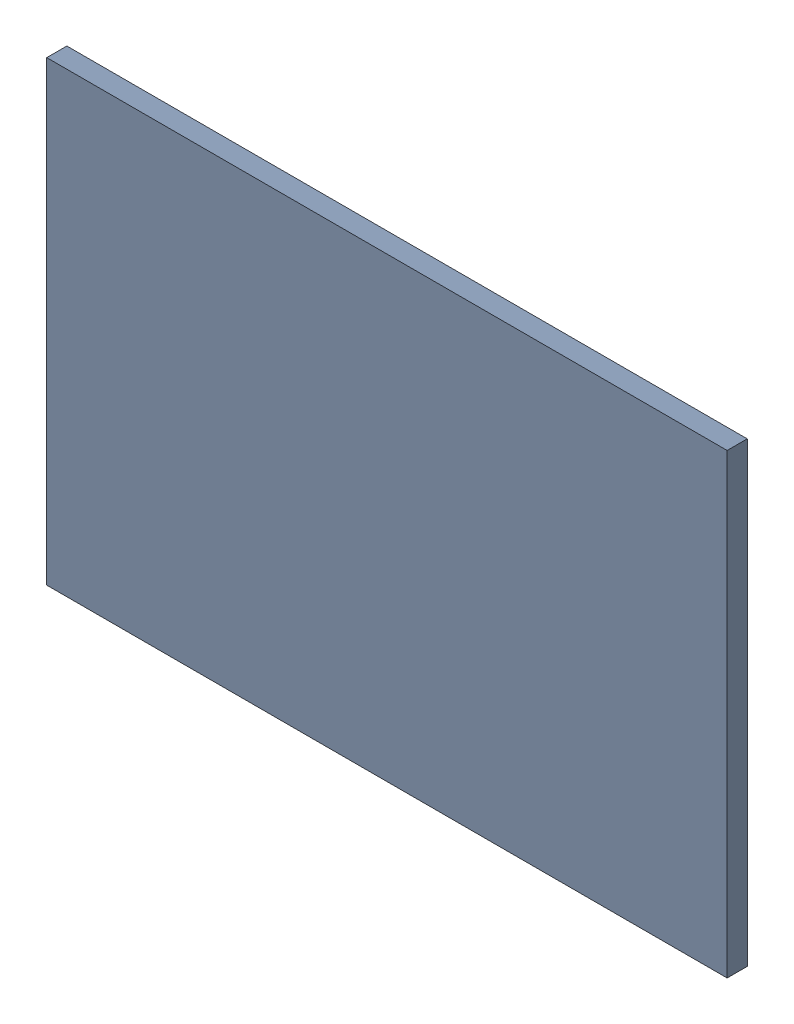
SolidWorks assembly terain complet, configuration Défaut. Lengths in mm.
Overall size (3044 2044 135).
55 component instances, 2 part files, 183 mates.
Components (placement in the parent):
- Pièce1-1: Pièce1 [Défaut] at (-264.4399 -325.1488 85) size (3044 2044 90)
- blocs-1: blocs [Défaut] at (410.3862 -144.8276 85) x (-1 0 0) z (0 0 -1) size (50 150 30)
- blocs-2: blocs [Défaut] at (357.991 -144.8276 55) size (50 150 30)
- blocs-3: blocs [Défaut] at (257.991 -144.8276 55) size (50 150 30)
- blocs-4: blocs [Défaut] at (310.3862 -144.8276 85) x (-1 0 0) z (0 0 -1) size (50 150 30)
- blocs-5: blocs [Défaut] at (-391.0933 -149.325 85) x (-1 0 0) z (0 0 -1) size (50 150 30)
- blocs-6: blocs [Défaut] at (-443.4885 -149.325 55) size (50 150 30)
- blocs-7: blocs [Défaut] at (-343.4885 -149.325 55) size (50 150 30)
- blocs-8: blocs [Défaut] at (-291.0933 -149.325 85) x (-1 0 0) z (0 0 -1) size (50 150 30)
- blocs-13: blocs [Défaut] at (-440.056 -818.8868 85) x (-1 0 0) z (0 0 -1) size (50 150 30)
- blocs-14: blocs [Défaut] at (-492.4513 -818.8868 55) size (50 150 30)
- blocs-15: blocs [Défaut] at (-392.4513 -818.8868 55) size (50 150 30)
- blocs-16: blocs [Défaut] at (-340.056 -818.8868 85) x (-1 0 0) z (0 0 -1) size (50 150 30)
- blocs-17: blocs [Défaut] at (408.6979 -820.0793 55) size (50 150 30)
- blocs-18: blocs [Défaut] at (461.0931 -820.0793 85) x (-1 0 0) z (0 0 -1) size (50 150 30)
- blocs-19: blocs [Défaut] at (361.0931 -820.0793 85) x (-1 0 0) z (0 0 -1) size (50 150 30)
- blocs-20: blocs [Défaut] at (308.6979 -820.0793 55) size (50 150 30)
- blocs-21: blocs [Défaut] at (-1350.1941 240.0301 85) x (0 1 0) z (0 0 -1) size (50 150 30)
- blocs-22: blocs [Défaut] at (-1350.1941 292.4253 55) x (0 -1 0) z (0 0 1) size (50 150 30)
- blocs-23: blocs [Défaut] at (-1350.1941 192.4253 55) x (0 -1 0) z (0 0 1) size (50 150 30)
- blocs-24: blocs [Défaut] at (-1350.1941 140.0301 85) x (0 1 0) z (0 0 -1) size (50 150 30)
- blocs-25: blocs [Défaut] at (-1428.6972 -611.7419 85) x (0 -1 0) z (0 0 -1) size (50 150 30)
- blocs-26: blocs [Défaut] at (-1428.6972 -664.1371 55) x (0 1 0) z (0 0 1) size (50 150 30)
- blocs-27: blocs [Défaut] at (-1428.6972 -564.1371 55) x (0 1 0) z (0 0 1) size (50 150 30)
- blocs-28: blocs [Défaut] at (-1428.6972 -511.7419 85) x (0 -1 0) z (0 0 -1) size (50 150 30)
- blocs-29: blocs [Défaut] at (1322.3512 -560.3529 55) x (0 1 0) z (0 0 1) size (50 150 30)
- blocs-30: blocs [Défaut] at (1322.3512 -660.3529 55) x (0 1 0) z (0 0 1) size (50 150 30)
- blocs-31: blocs [Défaut] at (1322.3512 -607.9577 85) x (0 -1 0) z (0 0 -1) size (50 150 30)
- blocs-32: blocs [Défaut] at (1396.9289 190.9777 55) x (0 -1 0) z (0 0 1) size (50 150 30)
- blocs-33: blocs [Défaut] at (1322.3512 -507.9577 85) x (0 -1 0) z (0 0 -1) size (50 150 30)
- blocs-34: blocs [Défaut] at (1396.9289 138.5825 85) x (0 1 0) z (0 0 -1) size (50 150 30)
- blocs-35: blocs [Défaut] at (1396.9289 238.5825 85) x (0 1 0) z (0 0 -1) size (50 150 30)
- blocs-36: blocs [Défaut] at (1396.9289 290.9777 55) x (0 -1 0) z (0 0 1) size (50 150 30)
- blocs-37: blocs [Défaut] at (758.3608 727.0316 30) x (-1 0 0) z (0 0 -1) size (50 150 30)
- blocs-38: blocs [Défaut] at (605.9656 727.0316 0) size (50 150 30)
- blocs-39: blocs [Défaut] at (658.3608 727.0316 30) x (-1 0 0) z (0 0 -1) size (50 150 30)
- blocs-40: blocs [Défaut] at (705.9656 727.0316 0) size (50 150 30)
- blocs-41: blocs [Défaut] at (-639.813 727.0035 30) x (-1 0 0) z (0 0 -1) size (50 150 30)
- blocs-42: blocs [Défaut] at (-792.2082 727.0035 0) size (50 150 30)
- blocs-43: blocs [Défaut] at (-739.813 727.0035 30) x (-1 0 0) z (0 0 -1) size (50 150 30)
- blocs-44: blocs [Défaut] at (-692.2082 727.0035 0) size (50 150 30)
- blocs-45: blocs [Défaut] at (-444.0364 775.1406 0) size (50 150 30)
- blocs-46: blocs [Défaut] at (-391.6411 775.1406 30) x (-1 0 0) z (0 0 -1) size (50 150 30)
- blocs-47: blocs [Défaut] at (-194.9963 829.483 0) size (50 150 30)
- blocs-48: blocs [Défaut] at (-142.6011 829.483 30) x (-1 0 0) z (0 0 -1) size (50 150 30)
- blocs-49: blocs [Défaut] at (159.98 831.8503 30) x (-1 0 0) z (0 0 -1) size (50 150 30)
- blocs-50: blocs [Défaut] at (107.5848 831.8503 0) size (50 150 30)
- blocs-51: blocs [Défaut] at (358.2688 779.4899 0) size (50 150 30)
- blocs-52: blocs [Défaut] at (410.664 779.4899 30) x (-1 0 0) z (0 0 -1) size (50 150 30)
- blocs-83: blocs [Défaut] at (-771.8818 727.0035 -30) size (50 150 30)
- blocs-84: blocs [Défaut] at (-721.8818 727.0035 -30) size (50 150 30)
- blocs-85: blocs [Défaut] at (-671.8818 727.0035 -30) size (50 150 30)
- blocs-86: blocs [Défaut] at (733.7754 727.0316 0) x (-1 0 0) z (0 0 -1) size (50 150 30)
- blocs-87: blocs [Défaut] at (683.7754 727.0316 0) x (-1 0 0) z (0 0 -1) size (50 150 30)
- blocs-88: blocs [Défaut] at (633.7754 727.0316 0) x (-1 0 0) z (0 0 -1) size (50 150 30)
Mates (geometry in assembly coordinates):
- Coïncidente1: coincident anti-aligned: plane of Pièce1-1 through (-264.4399 -325.1488 85) normal (0 0 -1); plane of blocs-1 through (410.3862 -144.8276 85) normal (0 0 1)
- Parallèle1: parallel aligned: plane of Pièce1-1 through (-1538.8671 -1007.343 15) normal (0 -1 0); plane of blocs-1 through (434.1886 -258.4504 55) normal (0 -1 0)
- Coïncidente3: coincident anti-aligned: plane of Pièce1-1 through (-264.4399 -325.1488 85) normal (0 0 -1); plane of blocs-2 through (357.991 -144.8276 85) normal (0 0 1)
- Parallèle3: parallel aligned: plane of Pièce1-1 through (-1538.8671 -1007.343 15) normal (0 -1 0); plane of blocs-2 through (334.1886 -258.4504 85) normal (0 -1 0)
- Coïncidente6: coincident anti-aligned: line of blocs-1 through (384.1886 -258.4504 55) axis (0 0 1); line of blocs-2 through (384.1886 -258.4504 85) axis (0 0 -1)
- Coïncidente7: coincident anti-aligned: line of blocs-3 through (284.1886 -258.4504 85) axis (0 0 -1); line of blocs-4 through (284.1886 -258.4504 55) axis (0 0 1)
- Coïncidente8: coincident anti-aligned: plane of blocs-2 through (334.1886 -108.4504 85) normal (-1 0 0); plane of blocs-4 through (334.1886 -108.4504 55) normal (1 0 0)
- Coïncidente9: coincident: plane of blocs-2 through (357.991 -144.8276 55) normal (0 0 -1); line of blocs-4 through (334.1886 -108.4504 55) axis (0 -1 0)
- Coïncidente10: coincident: plane of blocs-2 through (334.1886 -258.4504 85) normal (0 -1 0); line of blocs-4 through (334.1886 -258.4504 55) axis (0 0 1)
- Coïncidente11: coincident anti-aligned: line of blocs-3 through (284.1886 -258.4504 85) axis (0 0 -1); line of blocs-4 through (284.1886 -258.4504 55) axis (0 0 1)
- Coïncidente12: coincident anti-aligned: line of blocs-4 through (334.1886 -258.4504 55) axis (-1 0 0); line of blocs-3 through (234.1886 -258.4504 55) axis (1 0 0)
- Coïncidente13: coincident anti-aligned: line of blocs-5 through (-367.2909 -262.9478 55) axis (-1 0 0); line of blocs-6 through (-467.2909 -262.9478 55) axis (1 0 0)
- Coïncidente14: coincident anti-aligned: plane of blocs-5 through (-367.2909 -112.9478 55) normal (1 0 0); plane of blocs-7 through (-367.2909 -112.9478 85) normal (-1 0 0)
- Coïncidente15: coincident anti-aligned: line of blocs-5 through (-417.2909 -262.9478 55) axis (0 0 1); line of blocs-6 through (-417.2909 -262.9478 85) axis (0 0 -1)
- Coïncidente16: coincident: line of blocs-5 through (-367.2909 -112.9478 55) axis (0 -1 0); plane of blocs-7 through (-343.4885 -149.325 55) normal (0 0 -1)
- Coïncidente17: coincident: line of blocs-5 through (-367.2909 -262.9478 55) axis (0 0 1); plane of blocs-7 through (-367.2909 -262.9478 85) normal (0 -1 0)
- Coïncidente18: coincident anti-aligned: line of blocs-7 through (-317.2909 -262.9478 85) axis (0 0 -1); line of blocs-8 through (-317.2909 -262.9478 55) axis (0 0 1)
- Coïncidente19: coincident anti-aligned: line of blocs-5 through (-417.2909 -262.9478 55) axis (0 0 1); line of blocs-6 through (-417.2909 -262.9478 85) axis (0 0 -1)
- Coïncidente21: coincident aligned: line of blocs-7 through (-317.2909 -262.9478 55) axis (0 1 0); line of blocs-8 through (-317.2909 -262.9478 55) axis (0 1 0)
- Coïncidente22: coincident anti-aligned: plane of Pièce1-1 through (-264.4399 -325.1488 85) normal (0 0 -1); plane of blocs-5 through (-391.0933 -149.325 85) normal (0 0 1)
- Coïncidente29: coincident anti-aligned: line of blocs-11 through (-317.2909 -262.9478 85) axis (0 0 -1); line of blocs-12 through (-317.2909 -262.9478 55) axis (0 0 1)
- Coïncidente30: coincident aligned: line of blocs-11 through (-317.2909 -262.9478 55) axis (0 1 0); line of blocs-12 through (-317.2909 -262.9478 55) axis (0 1 0)
- Coïncidente31: coincident anti-aligned: line of blocs-13 through (-466.2537 -932.5096 55) axis (0 0 1); line of blocs-14 through (-466.2537 -932.5096 85) axis (0 0 -1)
- Coïncidente32: coincident: line of blocs-13 through (-416.2537 -782.5096 55) axis (0 -1 0); plane of blocs-15 through (-392.4513 -818.8868 55) normal (0 0 -1)
- Coïncidente33: coincident anti-aligned: plane of blocs-13 through (-416.2537 -782.5096 55) normal (1 0 0); plane of blocs-15 through (-416.2537 -782.5096 85) normal (-1 0 0)
- Coïncidente34: coincident anti-aligned: line of blocs-13 through (-466.2537 -932.5096 55) axis (0 0 1); line of blocs-14 through (-466.2537 -932.5096 85) axis (0 0 -1)
- Coïncidente35: coincident: line of blocs-13 through (-416.2537 -932.5096 55) axis (0 0 1); plane of blocs-15 through (-416.2537 -932.5096 85) normal (0 -1 0)
- Coïncidente36: coincident anti-aligned: line of blocs-13 through (-416.2537 -932.5096 55) axis (-1 0 0); line of blocs-14 through (-516.2537 -932.5096 55) axis (1 0 0)
- Coïncidente37: coincident anti-aligned: line of blocs-15 through (-366.2537 -932.5096 85) axis (0 0 -1); line of blocs-16 through (-366.2537 -932.5096 55) axis (0 0 1)
- Coïncidente38: coincident aligned: line of blocs-15 through (-366.2537 -932.5096 55) axis (0 1 0); line of blocs-16 through (-366.2537 -932.5096 55) axis (0 1 0)
- Coïncidente39: coincident anti-aligned: plane of Pièce1-1 through (-264.4399 -325.1488 85) normal (0 0 -1); plane of blocs-13 through (-440.056 -818.8868 85) normal (0 0 1)
- Coïncidente40: coincident anti-aligned: line of blocs-17 through (434.8955 -933.7021 85) axis (0 0 -1); line of blocs-18 through (434.8955 -933.7021 55) axis (0 0 1)
- Coïncidente41: coincident: line of blocs-17 through (384.8955 -783.7021 85) axis (0 -1 0); plane of blocs-19 through (361.0931 -820.0793 85) normal (0 0 1)
- Coïncidente42: coincident anti-aligned: plane of blocs-17 through (384.8955 -783.7021 85) normal (-1 0 0); plane of blocs-19 through (384.8955 -783.7021 55) normal (1 0 0)
- Coïncidente43: coincident anti-aligned: line of blocs-17 through (434.8955 -933.7021 85) axis (0 0 -1); line of blocs-18 through (434.8955 -933.7021 55) axis (0 0 1)
- Coïncidente44: coincident: line of blocs-17 through (384.8955 -933.7021 85) axis (0 0 -1); plane of blocs-19 through (384.8955 -933.7021 55) normal (0 -1 0)
- Coïncidente45: coincident anti-aligned: line of blocs-17 through (384.8955 -933.7021 85) axis (1 0 0); line of blocs-18 through (484.8955 -933.7021 85) axis (-1 0 0)
- Coïncidente46: coincident anti-aligned: line of blocs-19 through (334.8955 -933.7021 55) axis (0 0 1); line of blocs-20 through (334.8955 -933.7021 85) axis (0 0 -1)
- Coïncidente47: coincident aligned: line of blocs-19 through (334.8955 -933.7021 85) axis (0 1 0); line of blocs-20 through (334.8955 -933.7021 85) axis (0 1 0)
- Coïncidente48: coincident anti-aligned: plane of Pièce1-1 through (-264.4399 -325.1488 85) normal (0 0 -1); plane of blocs-17 through (408.6979 -820.0793 85) normal (0 0 1)
- Coïncidente49: coincident anti-aligned: plane of Pièce1-1 through (-264.4399 -325.1488 85) normal (0 0 -1); plane of blocs-19 through (361.0931 -820.0793 85) normal (0 0 1)
- Coïncidente50: coincident anti-aligned: line of blocs-21 through (-1463.8169 266.2277 55) axis (0 0 1); line of blocs-22 through (-1463.8169 266.2277 85) axis (0 0 -1)
- Coïncidente51: coincident: line of blocs-21 through (-1313.8169 216.2277 55) axis (-1 0 0); plane of blocs-23 through (-1350.1941 192.4253 55) normal (0 0 -1)
- Coïncidente52: coincident anti-aligned: plane of blocs-21 through (-1313.8169 216.2277 55) normal (0 -1 0); plane of blocs-23 through (-1313.8169 216.2277 85) normal (0 1 0)
- Coïncidente53: coincident anti-aligned: line of blocs-21 through (-1463.8169 266.2277 55) axis (0 0 1); line of blocs-22 through (-1463.8169 266.2277 85) axis (0 0 -1)
- Coïncidente54: coincident: line of blocs-21 through (-1463.8169 216.2277 55) axis (0 0 1); plane of blocs-23 through (-1463.8169 216.2277 85) normal (-1 0 0)
- Coïncidente55: coincident anti-aligned: line of blocs-21 through (-1463.8169 216.2277 55) axis (0 1 0); line of blocs-22 through (-1463.8169 316.2277 55) axis (0 -1 0)
- Coïncidente56: coincident anti-aligned: line of blocs-23 through (-1463.8169 166.2277 85) axis (0 0 -1); line of blocs-24 through (-1463.8169 166.2277 55) axis (0 0 1)
- Coïncidente57: coincident aligned: line of blocs-23 through (-1463.8169 166.2277 55) axis (1 0 0); line of blocs-24 through (-1463.8169 166.2277 55) axis (1 0 0)
- Coïncidente58: coincident anti-aligned: plane of Pièce1-1 through (-264.4399 -325.1488 85) normal (0 0 -1); plane of blocs-24 through (-1350.1941 140.0301 85) normal (0 0 1)
- Parallèle4: parallel aligned: plane of Pièce1-1 through (-1516.8671 1014.657 15) normal (1 0 0); plane of blocs-21 through (-1313.8169 216.2277 55) normal (1 0 0)
- Coïncidente60: coincident anti-aligned: line of blocs-25 through (-1315.0744 -637.9395 55) axis (0 0 1); line of blocs-26 through (-1315.0744 -637.9395 85) axis (0 0 -1)
- Coïncidente61: coincident: line of blocs-25 through (-1465.0744 -587.9395 55) axis (1 0 0); plane of blocs-27 through (-1428.6972 -564.1371 55) normal (0 0 -1)
- Coïncidente62: coincident anti-aligned: plane of blocs-25 through (-1465.0744 -587.9395 55) normal (0 1 0); plane of blocs-27 through (-1465.0744 -587.9395 85) normal (0 -1 0)
- Coïncidente63: coincident anti-aligned: line of blocs-25 through (-1315.0744 -637.9395 55) axis (0 0 1); line of blocs-26 through (-1315.0744 -637.9395 85) axis (0 0 -1)
- Coïncidente64: coincident: line of blocs-25 through (-1315.0744 -587.9395 55) axis (0 0 1); plane of blocs-27 through (-1315.0744 -587.9395 85) normal (1 0 0)
- Coïncidente65: coincident anti-aligned: line of blocs-25 through (-1315.0744 -587.9395 55) axis (0 -1 0); line of blocs-26 through (-1315.0744 -687.9395 55) axis (0 1 0)
- Coïncidente66: coincident anti-aligned: line of blocs-27 through (-1315.0744 -537.9395 85) axis (0 0 -1); line of blocs-28 through (-1315.0744 -537.9395 55) axis (0 0 1)
- Coïncidente67: coincident aligned: line of blocs-27 through (-1315.0744 -537.9395 55) axis (-1 0 0); line of blocs-28 through (-1315.0744 -537.9395 55) axis (-1 0 0)
- Coïncidente68: coincident anti-aligned: plane of Pièce1-1 through (-264.4399 -325.1488 85) normal (0 0 -1); plane of blocs-25 through (-1428.6972 -611.7419 85) normal (0 0 1)
- Parallèle5: parallel anti-aligned: plane of Pièce1-1 through (-1538.8671 1036.657 15) normal (-1 0 0); plane of blocs-25 through (-1315.0744 -587.9395 55) normal (1 0 0)
- Coïncidente70: coincident anti-aligned: plane of blocs-32 through (1433.3062 214.7801 85) normal (0 1 0); plane of blocs-35 through (1433.3062 214.7801 55) normal (0 -1 0)
- Coïncidente71: coincident aligned: line of blocs-32 through (1283.3062 164.7801 55) axis (1 0 0); line of blocs-34 through (1283.3062 164.7801 55) axis (1 0 0)
- Coïncidente72: coincident anti-aligned: line of blocs-35 through (1283.3062 214.7801 55) axis (0 1 0); line of blocs-36 through (1283.3062 314.7801 55) axis (0 -1 0)
- Coïncidente73: coincident: plane of blocs-29 through (1322.3512 -560.3529 55) normal (0 0 -1); line of blocs-31 through (1285.974 -584.1553 55) axis (1 0 0)
- Coïncidente74: coincident anti-aligned: line of blocs-35 through (1283.3062 264.7801 55) axis (0 0 1); line of blocs-36 through (1283.3062 264.7801 85) axis (0 0 -1)
- Coïncidente75: coincident: plane of blocs-32 through (1396.9289 190.9777 55) normal (0 0 -1); line of blocs-35 through (1433.3062 214.7801 55) axis (-1 0 0)
- Coïncidente76: coincident anti-aligned: line of blocs-35 through (1283.3062 264.7801 55) axis (0 0 1); line of blocs-36 through (1283.3062 264.7801 85) axis (0 0 -1)
- Coïncidente77: coincident: plane of blocs-32 through (1283.3062 214.7801 85) normal (-1 0 0); line of blocs-35 through (1283.3062 214.7801 55) axis (0 0 1)
- Coïncidente78: coincident anti-aligned: line of blocs-32 through (1283.3062 164.7801 85) axis (0 0 -1); line of blocs-34 through (1283.3062 164.7801 55) axis (0 0 1)
- Coïncidente80: coincident anti-aligned: line of blocs-30 through (1435.974 -634.1553 85) axis (0 0 -1); line of blocs-31 through (1435.974 -634.1553 55) axis (0 0 1)
- Coïncidente81: coincident: plane of blocs-29 through (1435.974 -584.1553 85) normal (1 0 0); line of blocs-31 through (1435.974 -584.1553 55) axis (0 0 1)
- Coïncidente82: coincident anti-aligned: line of blocs-30 through (1435.974 -634.1553 85) axis (0 0 -1); line of blocs-31 through (1435.974 -634.1553 55) axis (0 0 1)
- Coïncidente83: coincident anti-aligned: plane of blocs-29 through (1285.974 -584.1553 85) normal (0 -1 0); plane of blocs-31 through (1285.974 -584.1553 55) normal (0 1 0)
- Coïncidente84: coincident anti-aligned: line of blocs-30 through (1435.974 -684.1553 55) axis (0 1 0); line of blocs-31 through (1435.974 -584.1553 55) axis (0 -1 0)
- Coïncidente85: coincident aligned: line of blocs-29 through (1435.974 -534.1553 55) axis (-1 0 0); line of blocs-33 through (1435.974 -534.1553 55) axis (-1 0 0)
- Coïncidente86: coincident anti-aligned: plane of Pièce1-1 through (-264.4399 -325.1488 85) normal (0 0 -1); plane of blocs-29 through (1322.3512 -560.3529 85) normal (0 0 1)
- Parallèle6: parallel aligned: plane of Pièce1-1 through (1505.1329 -1007.343 15) normal (1 0 0); plane of blocs-31 through (1435.974 -584.1553 55) normal (1 0 0)
- Coïncidente88: coincident anti-aligned: plane of Pièce1-1 through (-264.4399 -325.1488 85) normal (0 0 -1); plane of blocs-32 through (1396.9289 190.9777 85) normal (0 0 1)
- Coïncidente90: coincident anti-aligned: plane of blocs-39 through (682.1632 763.4088 0) normal (1 0 0); plane of blocs-40 through (682.1632 763.4088 30) normal (-1 0 0)
- Coïncidente91: coincident anti-aligned: line of blocs-37 through (732.1632 613.4088 0) axis (0 0 1); line of blocs-40 through (732.1632 613.4088 30) axis (0 0 -1)
- Coïncidente92: coincident aligned: line of blocs-38 through (632.1632 613.4088 30) axis (0 1 0); line of blocs-39 through (632.1632 613.4088 30) axis (0 1 0)
- Coïncidente93: coincident anti-aligned: line of blocs-37 through (732.1632 613.4088 0) axis (0 0 1); line of blocs-40 through (732.1632 613.4088 30) axis (0 0 -1)
- Coïncidente94: coincident: plane of blocs-39 through (682.1632 613.4088 0) normal (0 -1 0); line of blocs-40 through (682.1632 613.4088 30) axis (0 0 -1)
- Coïncidente95: coincident anti-aligned: line of blocs-38 through (632.1632 613.4088 30) axis (0 0 -1); line of blocs-39 through (632.1632 613.4088 0) axis (0 0 1)
- Coïncidente96: coincident anti-aligned: line of blocs-37 through (782.1632 613.4088 30) axis (-1 0 0); line of blocs-40 through (682.1632 613.4088 30) axis (1 0 0)
- Coïncidente97: coincident: plane of blocs-39 through (658.3608 727.0316 30) normal (0 0 1); line of blocs-40 through (682.1632 763.4088 30) axis (0 -1 0)
- Coïncidente98: coincident anti-aligned: plane of Pièce1-1 through (-264.4399 -325.1488 30) normal (0 0 -1); plane of blocs-40 through (705.9656 727.0316 30) normal (0 0 1)
- Coïncidente99: coincident anti-aligned: plane of blocs-43 through (-716.0106 763.3808 0) normal (1 0 0); plane of blocs-44 through (-716.0106 763.3808 30) normal (-1 0 0)
- Coïncidente100: coincident anti-aligned: line of blocs-41 through (-666.0106 613.3808 0) axis (0 0 1); line of blocs-44 through (-666.0106 613.3808 30) axis (0 0 -1)
- Coïncidente101: coincident aligned: line of blocs-42 through (-766.0106 613.3808 30) axis (0 1 0); line of blocs-43 through (-766.0106 613.3808 30) axis (0 1 0)
- Coïncidente102: coincident anti-aligned: line of blocs-41 through (-666.0106 613.3808 0) axis (0 0 1); line of blocs-44 through (-666.0106 613.3808 30) axis (0 0 -1)
- Coïncidente103: coincident: plane of blocs-43 through (-716.0106 613.3808 0) normal (0 -1 0); line of blocs-44 through (-716.0106 613.3808 30) axis (0 0 -1)
- Coïncidente104: coincident anti-aligned: line of blocs-42 through (-766.0106 613.3808 30) axis (0 0 -1); line of blocs-43 through (-766.0106 613.3808 0) axis (0 0 1)
- Coïncidente105: coincident anti-aligned: line of blocs-41 through (-616.0106 613.3808 30) axis (-1 0 0); line of blocs-44 through (-716.0106 613.3808 30) axis (1 0 0)
- Coïncidente106: coincident: plane of blocs-43 through (-739.813 727.0035 30) normal (0 0 1); line of blocs-44 through (-716.0106 763.3808 30) axis (0 -1 0)
- Coïncidente107: coincident anti-aligned: plane of Pièce1-1 through (-264.4399 -325.1488 30) normal (0 0 -1); plane of blocs-43 through (-739.813 727.0035 30) normal (0 0 1)
- Coïncidente108: coincident anti-aligned: plane of Pièce1-1 through (-264.4399 -325.1488 30) normal (0 0 -1); plane of blocs-45 through (-444.0364 775.1406 30) normal (0 0 1)
- Coïncidente110: coincident anti-aligned: plane of Pièce1-1 through (-264.4399 -325.1488 30) normal (0 0 -1); plane of blocs-46 through (-391.6411 775.1406 30) normal (0 0 1)
- Coïncidente111: coincident anti-aligned: plane of blocs-45 through (-417.8387 811.5178 30) normal (1 0 0); plane of blocs-46 through (-417.8387 811.5178 0) normal (-1 0 0)
- Parallèle7: parallel aligned: plane of Pièce1-1 through (1483.1329 1014.657 15) normal (0 -1 0); plane of blocs-46 through (-367.8387 661.5178 0) normal (0 -1 0)
- Coïncidente113: coincident anti-aligned: line of blocs-45 through (-417.8387 661.5178 30) axis (0 0 -1); line of blocs-46 through (-417.8387 661.5178 0) axis (0 0 1)
- Coïncidente114: coincident anti-aligned: plane of blocs-47 through (-168.7987 865.8603 30) normal (1 0 0); plane of blocs-48 through (-168.7987 865.8603 0) normal (-1 0 0)
- Coïncidente115: coincident anti-aligned: line of blocs-47 through (-168.7987 715.8603 30) axis (0 0 -1); line of blocs-48 through (-168.7987 715.8603 0) axis (0 0 1)
- Coïncidente116: coincident aligned: line of blocs-47 through (-168.7987 715.8603 0) axis (0 1 0); line of blocs-48 through (-168.7987 715.8603 0) axis (0 1 0)
- Coïncidente118: coincident anti-aligned: plane of Pièce1-1 through (-264.4399 -325.1488 30) normal (0 0 -1); plane of blocs-47 through (-194.9963 829.483 30) normal (0 0 1)
- Coïncidente119: coincident anti-aligned: plane of blocs-49 through (133.7824 868.2275 0) normal (-1 0 0); plane of blocs-50 through (133.7824 868.2275 30) normal (1 0 0)
- Coïncidente120: coincident anti-aligned: line of blocs-49 through (133.7824 718.2275 0) axis (0 0 1); line of blocs-50 through (133.7824 718.2275 30) axis (0 0 -1)
- Coïncidente121: coincident aligned: line of blocs-49 through (133.7824 718.2275 30) axis (0 1 0); line of blocs-50 through (133.7824 718.2275 30) axis (0 1 0)
- Coïncidente123: coincident anti-aligned: plane of Pièce1-1 through (-264.4399 -325.1488 30) normal (0 0 -1); plane of blocs-50 through (107.5848 831.8503 30) normal (0 0 1)
- Coïncidente124: coincident aligned: line of blocs-51 through (384.4664 665.8671 30) axis (0 1 0); line of blocs-52 through (384.4664 665.8671 30) axis (0 1 0)
- Coïncidente125: coincident anti-aligned: line of blocs-51 through (384.4664 665.8671 30) axis (0 0 -1); line of blocs-52 through (384.4664 665.8671 0) axis (0 0 1)
- Coïncidente126: coincident anti-aligned: plane of blocs-51 through (384.4664 815.8671 30) normal (1 0 0); plane of blocs-52 through (384.4664 815.8671 0) normal (-1 0 0)
- Coïncidente127: coincident anti-aligned: plane of Pièce1-1 through (-264.4399 -325.1488 30) normal (0 0 -1); plane of blocs-52 through (410.664 779.4899 30) normal (0 0 1)
- Coïncidente128: coincident anti-aligned: line of blocs-60 through (1435.974 -634.1553 85) axis (0 0 -1); line of blocs-61 through (1435.974 -634.1553 55) axis (0 0 1)
- Coïncidente129: coincident: plane of blocs-59 through (1435.974 -584.1553 85) normal (1 0 0); line of blocs-61 through (1435.974 -584.1553 55) axis (0 0 1)
- Coïncidente130: coincident anti-aligned: plane of blocs-59 through (1285.974 -584.1553 85) normal (0 -1 0); plane of blocs-61 through (1285.974 -584.1553 55) normal (0 1 0)
- Coïncidente131: coincident anti-aligned: line of blocs-68 through (632.1632 615.9994 30) axis (0 0 -1); line of blocs-69 through (632.1632 615.9994 0) axis (0 0 1)
- Coïncidente132: coincident anti-aligned: line of blocs-60 through (1435.974 -684.1553 55) axis (0 1 0); line of blocs-61 through (1435.974 -584.1553 55) axis (0 -1 0)
- Coïncidente133: coincident aligned: line of blocs-59 through (1435.974 -534.1553 55) axis (-1 0 0); line of blocs-63 through (1435.974 -534.1553 55) axis (-1 0 0)
- Coïncidente134: coincident: plane of blocs-69 through (658.3608 729.6221 30) normal (0 0 1); line of blocs-70 through (682.1632 765.9994 30) axis (0 -1 0)
- Coïncidente135: coincident anti-aligned: line of blocs-71 through (-666.0106 613.3808 0) axis (0 0 1); line of blocs-74 through (-666.0106 613.3808 30) axis (0 0 -1)
- Coïncidente136: coincident: plane of blocs-73 through (-716.0106 613.3808 0) normal (0 -1 0); line of blocs-74 through (-716.0106 613.3808 30) axis (0 0 -1)
- Coïncidente137: coincident anti-aligned: line of blocs-67 through (732.1632 615.9994 0) axis (0 0 1); line of blocs-70 through (732.1632 615.9994 30) axis (0 0 -1)
- Coïncidente138: coincident aligned: line of blocs-72 through (-766.0106 613.3808 30) axis (0 1 0); line of blocs-73 through (-766.0106 613.3808 30) axis (0 1 0)
- Coïncidente139: coincident anti-aligned: line of blocs-67 through (732.1632 615.9994 0) axis (0 0 1); line of blocs-70 through (732.1632 615.9994 30) axis (0 0 -1)
- Coïncidente140: coincident anti-aligned: line of blocs-71 through (-666.0106 613.3808 0) axis (0 0 1); line of blocs-74 through (-666.0106 613.3808 30) axis (0 0 -1)
- Coïncidente141: coincident aligned: line of blocs-68 through (632.1632 615.9994 30) axis (0 1 0); line of blocs-69 through (632.1632 615.9994 30) axis (0 1 0)
- Coïncidente142: coincident anti-aligned: plane of blocs-69 through (682.1632 765.9994 0) normal (1 0 0); plane of blocs-70 through (682.1632 765.9994 30) normal (-1 0 0)
- Coïncidente143: coincident: plane of blocs-69 through (682.1632 615.9994 0) normal (0 -1 0); line of blocs-70 through (682.1632 615.9994 30) axis (0 0 -1)
- Coïncidente144: coincident anti-aligned: line of blocs-67 through (782.1632 615.9994 30) axis (-1 0 0); line of blocs-70 through (682.1632 615.9994 30) axis (1 0 0)
- Coïncidente145: coincident anti-aligned: plane of blocs-73 through (-716.0106 763.3808 0) normal (1 0 0); plane of blocs-74 through (-716.0106 763.3808 30) normal (-1 0 0)
- Coïncidente146: coincident: plane of blocs-73 through (-739.813 727.0035 30) normal (0 0 1); line of blocs-74 through (-716.0106 763.3808 30) axis (0 -1 0)
- Coïncidente147: coincident anti-aligned: line of blocs-71 through (-616.0106 613.3808 30) axis (-1 0 0); line of blocs-74 through (-716.0106 613.3808 30) axis (1 0 0)
- Coïncidente148: coincident anti-aligned: line of blocs-72 through (-766.0106 613.3808 30) axis (0 0 -1); line of blocs-73 through (-766.0106 613.3808 0) axis (0 0 1)
- Coïncidente149: coincident anti-aligned: line of blocs-60 through (1435.974 -634.1553 85) axis (0 0 -1); line of blocs-61 through (1435.974 -634.1553 55) axis (0 0 1)
- Coïncidente150: coincident anti-aligned: line of blocs-81 through (384.9754 664.3639 30) axis (0 0 -1); line of blocs-82 through (384.9754 664.3639 0) axis (0 0 1)
- Coïncidente151: coincident aligned: line of blocs-79 through (133.7824 718.2275 30) axis (0 1 0); line of blocs-80 through (133.7824 718.2275 30) axis (0 1 0)
- Coïncidente152: coincident anti-aligned: plane of blocs-81 through (384.9754 814.3639 30) normal (1 0 0); plane of blocs-82 through (384.9754 814.3639 0) normal (-1 0 0)
- Coïncidente153: coincident aligned: line of blocs-81 through (384.9754 664.3639 30) axis (0 1 0); line of blocs-82 through (384.9754 664.3639 30) axis (0 1 0)
- Coïncidente155: coincident: line of blocs-55 through (-1465.0744 -587.9395 55) axis (1 0 0); plane of blocs-57 through (-1428.6972 -564.1371 55) normal (0 0 -1)
- Coïncidente157: coincident anti-aligned: line of blocs-57 through (-1315.0744 -537.9395 85) axis (0 0 -1); line of blocs-58 through (-1315.0744 -537.9395 55) axis (0 0 1)
- Coïncidente158: coincident aligned: line of blocs-62 through (1283.3062 164.7801 55) axis (1 0 0); line of blocs-64 through (1283.3062 164.7801 55) axis (1 0 0)
- Coïncidente159: coincident: plane of blocs-59 through (1322.3512 -560.3529 55) normal (0 0 -1); line of blocs-61 through (1285.974 -584.1553 55) axis (1 0 0)
- Coïncidente160: coincident anti-aligned: line of blocs-55 through (-1315.0744 -637.9395 55) axis (0 0 1); line of blocs-56 through (-1315.0744 -637.9395 85) axis (0 0 -1)
- Coïncidente161: coincident: line of blocs-55 through (-1315.0744 -587.9395 55) axis (0 0 1); plane of blocs-57 through (-1315.0744 -587.9395 85) normal (1 0 0)
- Coïncidente162: coincident anti-aligned: line of blocs-55 through (-1315.0744 -637.9395 55) axis (0 0 1); line of blocs-56 through (-1315.0744 -637.9395 85) axis (0 0 -1)
- Coïncidente163: coincident anti-aligned: plane of blocs-55 through (-1465.0744 -587.9395 55) normal (0 1 0); plane of blocs-57 through (-1465.0744 -587.9395 85) normal (0 -1 0)
- Coïncidente164: coincident anti-aligned: line of blocs-65 through (1283.3062 264.7801 55) axis (0 0 1); line of blocs-66 through (1283.3062 264.7801 85) axis (0 0 -1)
- Coïncidente165: coincident: plane of blocs-62 through (1396.9289 190.9777 55) normal (0 0 -1); line of blocs-65 through (1433.3062 214.7801 55) axis (-1 0 0)
- Coïncidente166: coincident anti-aligned: plane of blocs-62 through (1433.3062 214.7801 85) normal (0 1 0); plane of blocs-65 through (1433.3062 214.7801 55) normal (0 -1 0)
- Coïncidente167: coincident anti-aligned: line of blocs-55 through (-1315.0744 -587.9395 55) axis (0 -1 0); line of blocs-56 through (-1315.0744 -687.9395 55) axis (0 1 0)
- Coïncidente168: coincident anti-aligned: line of blocs-65 through (1283.3062 264.7801 55) axis (0 0 1); line of blocs-66 through (1283.3062 264.7801 85) axis (0 0 -1)
- Coïncidente169: coincident: plane of blocs-62 through (1283.3062 214.7801 85) normal (-1 0 0); line of blocs-65 through (1283.3062 214.7801 55) axis (0 0 1)
- Coïncidente170: coincident anti-aligned: line of blocs-65 through (1283.3062 214.7801 55) axis (0 1 0); line of blocs-66 through (1283.3062 314.7801 55) axis (0 -1 0)
- Coïncidente171: coincident anti-aligned: line of blocs-62 through (1283.3062 164.7801 85) axis (0 0 -1); line of blocs-64 through (1283.3062 164.7801 55) axis (0 0 1)
- Coïncidente172: coincident aligned: line of blocs-57 through (-1315.0744 -537.9395 55) axis (-1 0 0); line of blocs-58 through (-1315.0744 -537.9395 55) axis (-1 0 0)
- Coïncidente173: coincident anti-aligned: plane of blocs-75 through (-415.9233 817.2988 30) normal (1 0 0); plane of blocs-76 through (-415.9233 817.2988 0) normal (-1 0 0)
- Coïncidente174: coincident anti-aligned: plane of blocs-77 through (-168.7987 865.8603 30) normal (1 0 0); plane of blocs-78 through (-168.7987 865.8603 0) normal (-1 0 0)
- Coïncidente175: coincident anti-aligned: line of blocs-75 through (-415.9233 667.2988 30) axis (0 0 -1); line of blocs-76 through (-415.9233 667.2988 0) axis (0 0 1)
- Coïncidente176: coincident anti-aligned: line of blocs-79 through (133.7824 718.2275 0) axis (0 0 1); line of blocs-80 through (133.7824 718.2275 30) axis (0 0 -1)
- Coïncidente177: coincident anti-aligned: plane of blocs-79 through (133.7824 868.2275 0) normal (-1 0 0); plane of blocs-80 through (133.7824 868.2275 30) normal (1 0 0)
- Coïncidente178: coincident anti-aligned: line of blocs-77 through (-168.7987 715.8603 30) axis (0 0 -1); line of blocs-78 through (-168.7987 715.8603 0) axis (0 0 1)
- Coïncidente179: coincident aligned: line of blocs-77 through (-168.7987 715.8603 0) axis (0 1 0); line of blocs-78 through (-168.7987 715.8603 0) axis (0 1 0)
- Verrouiller1: lock: unknown of Pièce1-1; unknown of blocs-52
- Verrouiller2: lock: unknown of Pièce1-1; unknown of blocs-43
- Verrouiller3: lock: unknown of Pièce1-1; unknown of blocs-45
- Coïncidente182: coincident anti-aligned: line of blocs-83 through (-745.6842 613.3808 -30) axis (0 1 0); line of blocs-84 through (-745.6842 763.3808 -30) axis (0 -1 0)
- Coïncidente184: coincident anti-aligned: plane of blocs-84 through (-695.6842 763.3808 0) normal (1 0 0); plane of blocs-85 through (-695.6842 763.3808 0) normal (-1 0 0)
- Coïncidente185: coincident: plane of blocs-84 through (-745.6842 613.3808 0) normal (0 -1 0); line of blocs-85 through (-695.6842 613.3808 0) axis (0 0 -1)
- Coïncidente186: coincident aligned: plane of blocs-83 through (-795.6842 613.3808 0) normal (0 -1 0); plane of blocs-84 through (-745.6842 613.3808 0) normal (0 -1 0)
- Coïncidente187: coincident anti-aligned: plane of blocs-42 through (-792.2082 727.0035 0) normal (0 0 -1); plane of blocs-83 through (-771.8818 727.0035 0) normal (0 0 1)
- Coïncidente188: coincident anti-aligned: line of blocs-84 through (-695.6842 613.3808 -30) axis (0 1 0); line of blocs-85 through (-695.6842 763.3808 -30) axis (0 -1 0)
- Coïncidente189: coincident anti-aligned: line of blocs-43 through (-716.0106 613.3808 0) axis (-1 0 0); line of blocs-84 through (-745.6842 613.3808 0) axis (1 0 0)
- Coïncidente190: coincident anti-aligned: line of blocs-87 through (657.5778 613.4088 0) axis (0 1 0); line of blocs-88 through (657.5778 763.4088 0) axis (0 -1 0)
- Coïncidente191: coincident anti-aligned: line of blocs-86 through (707.5778 613.4088 0) axis (0 1 0); line of blocs-87 through (707.5778 763.4088 0) axis (0 -1 0)
- Coïncidente192: coincident aligned: plane of blocs-87 through (707.5778 613.4088 -30) normal (0 -1 0); plane of blocs-88 through (657.5778 613.4088 -30) normal (0 -1 0)
- Coïncidente193: coincident aligned: plane of blocs-86 through (757.5778 613.4088 -30) normal (0 -1 0); plane of blocs-87 through (707.5778 613.4088 -30) normal (0 -1 0)
- Coïncidente195: coincident anti-aligned: plane of blocs-39 through (658.3608 727.0316 0) normal (0 0 -1); plane of blocs-87 through (683.7754 727.0316 0) normal (0 0 1)
- Coïncidente196: coincident aligned: line of blocs-87 through (707.5778 613.4088 -30) axis (-1 0 0); line of blocs-88 through (657.5778 613.4088 -30) axis (-1 0 0)
- Coïncidente197: coincident aligned: line of blocs-86 through (757.5778 613.4088 -30) axis (-1 0 0); line of blocs-87 through (707.5778 613.4088 -30) axis (-1 0 0)
- Coïncidente198: coincident anti-aligned: plane of blocs-39 through (658.3608 727.0316 0) normal (0 0 -1); plane of blocs-87 through (683.7754 727.0316 0) normal (0 0 1)
- Coïncidente199: coincident aligned: line of blocs-39 through (682.1632 613.4088 0) axis (-1 0 0); line of blocs-87 through (707.5778 613.4088 0) axis (-1 0 0)
